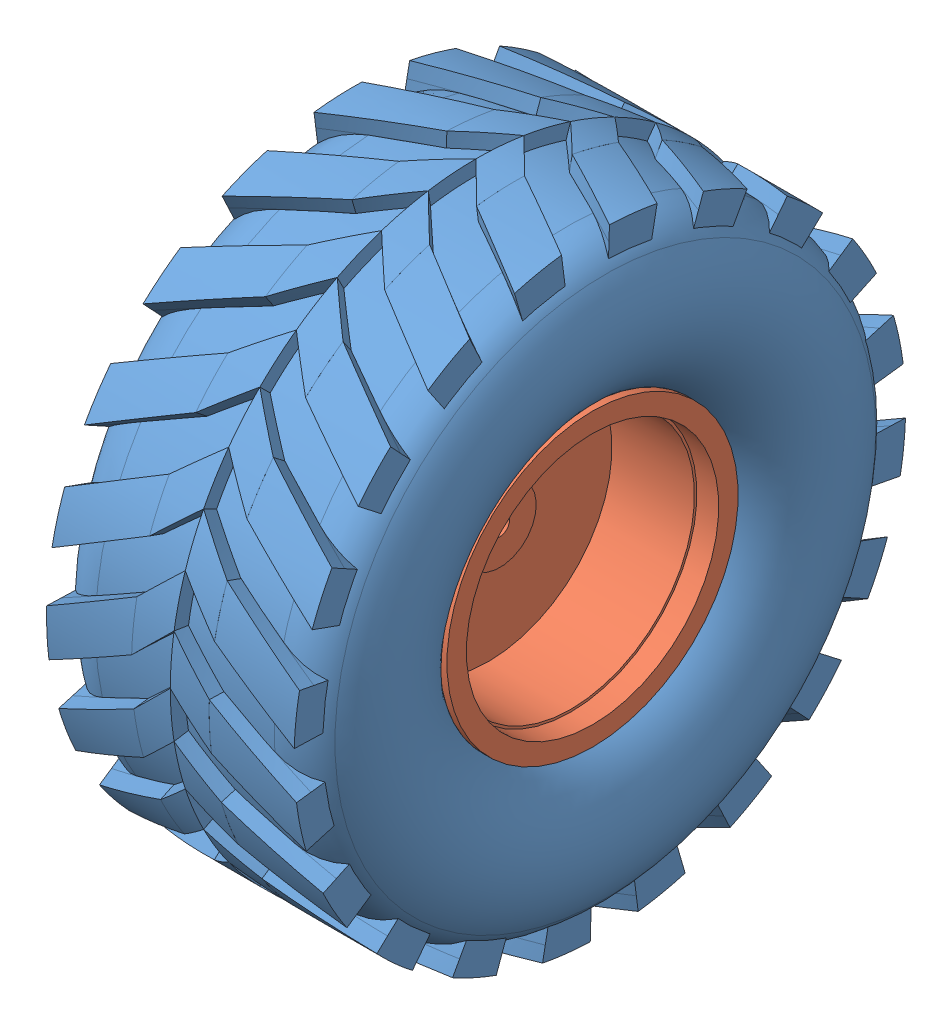
SolidWorks assembly Ensamblaje1, configuration Predeterminado. Lengths in mm.
Overall size (60 132.17 132.17).
2 component instances, 2 part files, 2 mates.
Components (placement in the parent):
- Pneumatico-1: Pneumatico [Predeterminado] at (-19.0093 14.9848 0) size (60 132.17 132.17)
- Llanta-1: Llanta [Predeterminado] at (-19.0093 14.9848 0) x (1 0 0) z (0 0 -1) size (48 60 60)
Mates (geometry in assembly coordinates):
- Coincidente1: coincident: circle of Pneumatico-1; circle of Llanta-1
- Coincidente2: coincident anti-aligned: plane of Pneumatico-1 through (-19.0093 14.9848 0) normal (0 0 1); plane of Llanta-1 through (-19.0093 14.9848 0) normal (0 0 -1)
